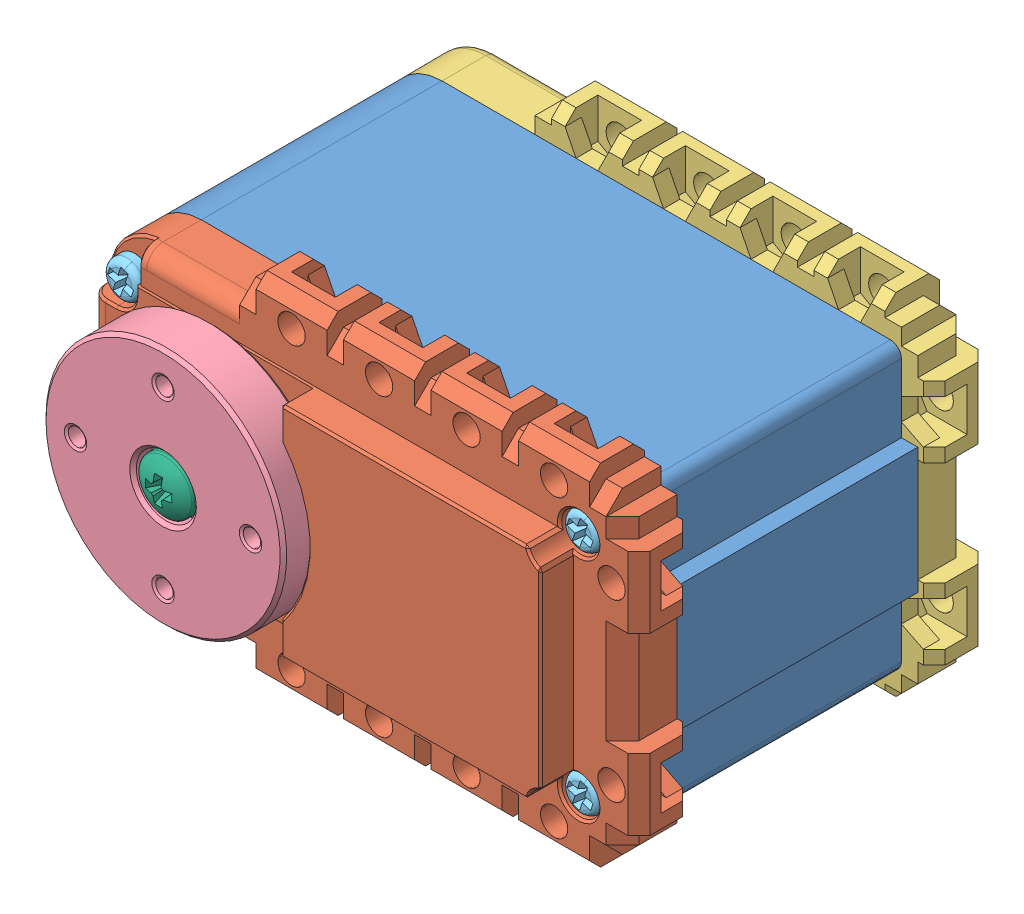
SolidWorks assembly DYNAMIXEL AX-12A, configuration Défaut. Lengths in mm.
Overall size (50 32 40.55).
9 component instances, 6 part files, 0 mates.
Components (placement in the parent):
- AX-12A-01-1: AX-12A-01 [Défaut] at origin size (48.5 26 22)
- AX-12A-02-1: AX-12A-02 [Défaut] at (0 0 13.5) size (50 32 8)
- AX-12A-03-1: AX-12A-03 [Défaut] at (0 0 -13.5) x (1 0 0) z (0 0 -1) size (50 32 8)
- AX-12A-04-1: AX-12A-04 [Défaut] at (0 0 21) size (22 22 6.7)
- SetScrew-1: SetScrew [Défaut] at (33 10.4 14.5) x (0.31498 0.949098 0) z (0 0 -1) size (3.3 3.3 29.44)
- SetScrew-2: SetScrew [Défaut] at (-9 9.25 14.5) x (0.31498 0.949098 0) z (0 0 -1) size (3.3 3.3 29.44)
- SetScrew-3: SetScrew [Défaut] at (-9 -9.25 14.5) x (-0.958559 0.284893 0) z (0 0 -1) size (3.3 3.3 29.44)
- SetScrew-4: SetScrew [Défaut] at (33 -10.4 14.5) x (0.31498 0.949098 0) z (0 0 -1) size (3.3 3.3 29.44)
- M2.5 x 8-1: M2.5 x 8 [Défaut] at (0 0 21.6) x (0 0 -1) z (1 0 0) size (10.05 5 5)
